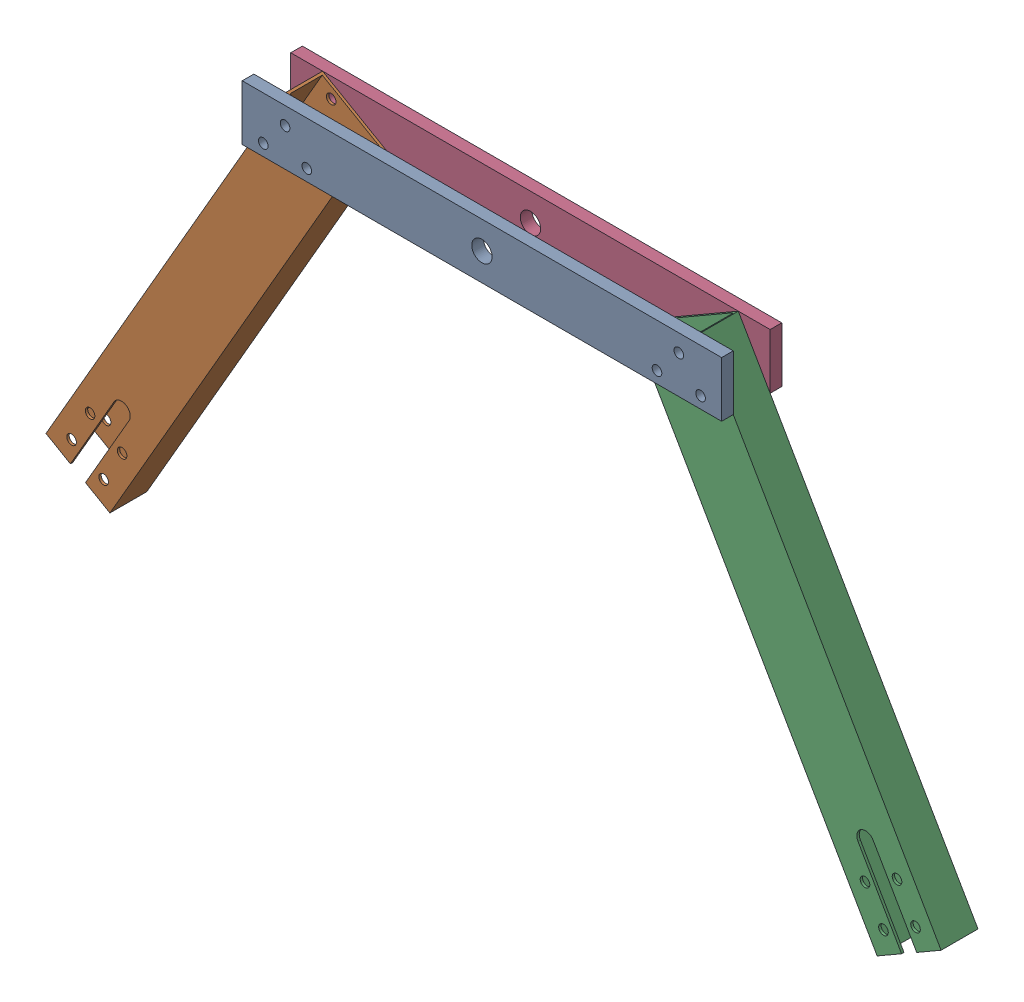
SolidWorks assembly Suspension Leg Assembly, configuration Default. Lengths in mm.
Overall size (616.12 311.19 41.4).
4 component instances, 3 part files, 8 mates.
Components (placement in the parent):
- Suspension Horiztonal CH-0006 (CUB)-1: Suspension Horiztonal CH-0006 (CUB) [Default] at (-21.3933 19.6954 4) size (330 38 8)
- Left Suspensin Leg CH-0004 (CUB)-1: Left Suspensin Leg CH-0004 (CUB) [Default] at (-142.4569 25.9954 -8.7) x (0.866025 -0.5 0) z (-0.5 -0.866025 0) size (50.8 25.4 330)
- right Suspensin Leg CH-0005 (CUB)-1: right Suspensin Leg CH-0005 (CUB) [Default] at (99.6704 25.9954 -8.7) x (0.866025 0.5 0) z (0.5 -0.866025 0) size (50.8 25.4 330)
- Suspension Horiztonal CH-0006 (CUB)-2: Suspension Horiztonal CH-0006 (CUB) [Default] at (-21.3933 19.6954 -29.4) size (330 38 8)
Mates (geometry in assembly coordinates):
- Coincident1: coincident anti-aligned: plane of Suspension Horiztonal Bbar-1 through (-21.3933 19.6954 4) normal (0 0 -1); plane of Left Suspensin Leg CH-0004 (CUB)-1 through (-329.4539 -247.093 4) normal (0 0 1)
- Angle1: planar angle = 2.094395 rad anti-aligned: line of Suspension Horiztonal Bbar-1 through (-186.3933 0.6954 4) axis (1 0 0); line of Left Suspensin Leg CH-0004 (CUB)-1 through (-285.4599 -272.493 4) axis (0.5 0.866025 0)
- Coincident3: coincident: line of Suspension Horiztonal Bbar-1 through (143.6067 38.6954 4) axis (-1 0 0); point of Left Suspensin Leg CH-0004 (CUB)-1
- Coincident4: coincident: point of Suspension Horiztonal Bbar-1; line of Left Suspensin Leg CH-0004 (CUB)-1 through (-329.4539 -247.093 4) axis (0.5 0.866025 0)
- Coincident5: coincident anti-aligned: plane of Suspension Horiztonal Bbar-1 through (-21.3933 19.6954 4) normal (0 0 -1); plane of right Suspensin Leg CH-0005 (CUB)-1 through (242.6733 -272.493 4) normal (0 0 1)
- Angle2: planar angle = 2.094395 rad aligned: line of right Suspensin Leg CH-0005 (CUB)-1 through (242.6733 -272.493 4) axis (-0.5 0.866025 0); line of Suspension Horiztonal Bbar-1 through (-186.3933 0.6954 12) axis (1 0 0)
- Coincident7: coincident: line of Suspension Horiztonal Bbar-1 through (143.6067 38.6954 4) axis (-1 0 0); point of right Suspensin Leg CH-0005 (CUB)-1
- Coincident8: coincident: point of Suspension Horiztonal Bbar-1; line of right Suspensin Leg CH-0005 (CUB)-1 through (286.6674 -247.093 4) axis (-0.5 0.866025 0)
